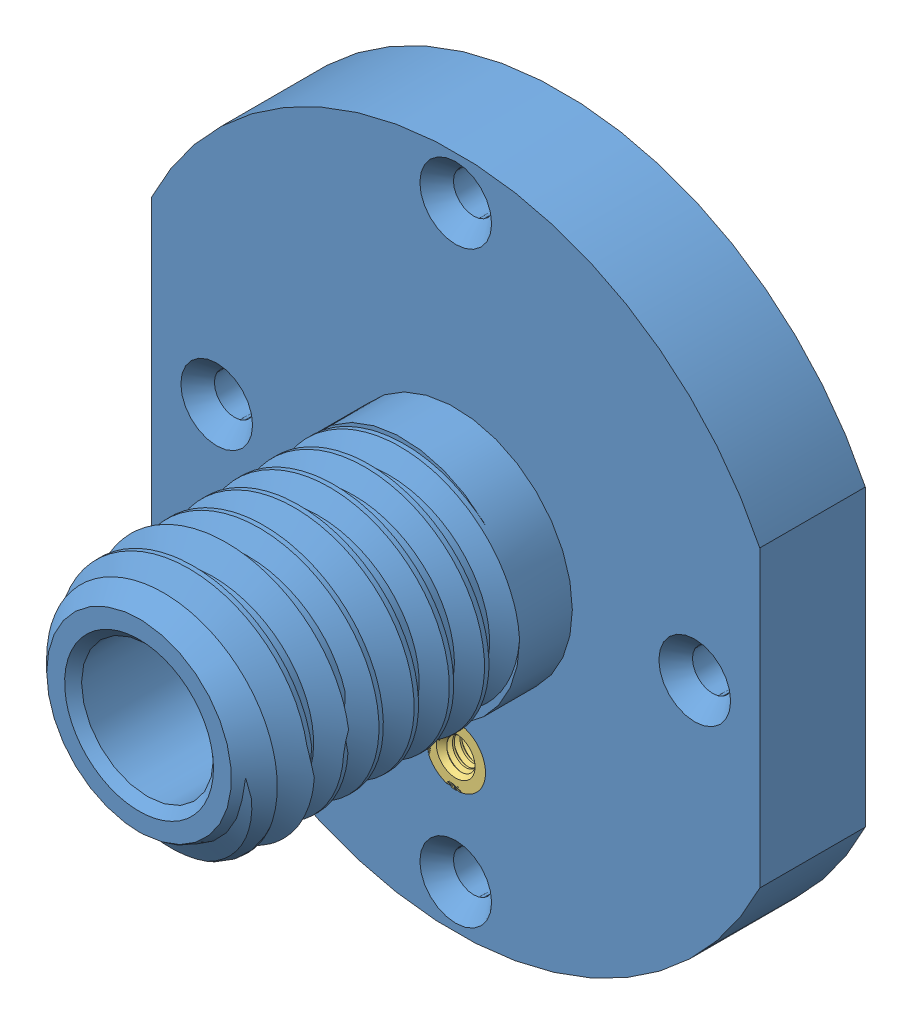
SolidWorks assembly Wing Fold Mechanism Upper Cap, configuration Default. Lengths in mm.
Overall size (36.58 40.64 28.08).
3 component instances, 3 part files, 0 mates.
Components (placement in the parent):
- Wing Fold Mechanism Upper Cap-1: Wing Fold Mechanism Upper Cap [Default] at origin size (36.58 40.64 28.08)
- 6338K411-1: 6338K411 [Default] at (0 0 55.5625) x (1 0 0) z (0 -1 0) size (12.7 6.35 12.7)
- 93365A112-1: 93365A112 [Default] at (0 -11.1125 61.9125) x (1 0 0) z (0 -1 0) size (3.58 4.78 3.58)
